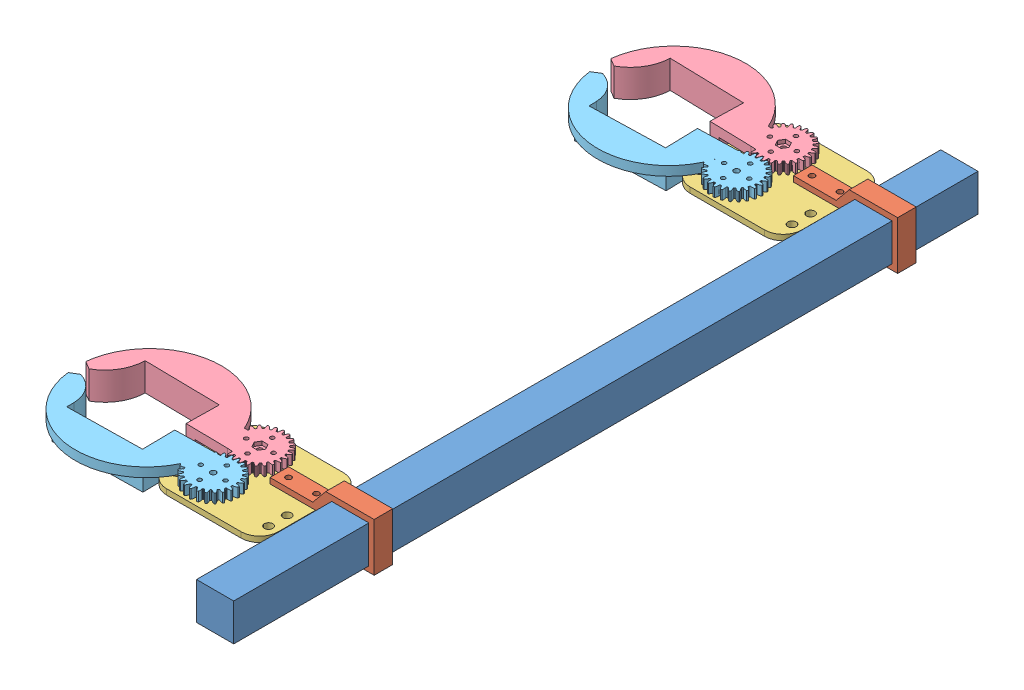
SolidWorks assembly 连接件部分ver1, configuration Default. Lengths in mm.
Overall size (157.66 26.1 400).
9 component instances, 5 part files, 23 mates.
Components (placement in the parent):
- 横杆的简易模型-1: 横杆的简易模型 [默认] at origin size (20 20 400)
- 连接件-1: 连接件 [默认] at (-24.8405 13.4666 36.1997) size (56 26 10)
- 固定舵机盘-1: 固定舵机盘 [默认] at (-24.824 10.0166 49.6672) x (-1 0 0) z (0 1 0) size (60 55 7)
- 右臂直齿M1X25-1: 右臂直齿M1X25 [M1X25] at (-70.3405 20.0166 36.0997) x (-0.026433 0 0.999651) z (0 -1 0) size (39.61 99.26 15)
- 左臂直齿M1X25-1: 左臂直齿M1X25 [M1X25] at (-70.3405 15.0166 61.1997) x (-0.026433 0 -0.999651) z (0 1 0) size (39.22 98.93 15)
- 左臂直齿M1X25-2: 左臂直齿M1X25 [M1X25] at (-70.4405 15.1166 342.4288) x (-0.015806 0 -0.999875) z (0 1 0) size (39.22 98.93 15)
- 右臂直齿M1X25-2: 右臂直齿M1X25 [M1X25] at (-70.4405 20.1166 317.3288) x (-0.015806 0 0.999875) z (0 -1 0) size (39.61 99.26 15)
- 固定舵机盘-2: 固定舵机盘 [默认] at (-24.924 10.1166 330.8963) x (-1 0 0) z (0 1 0) size (60 55 7)
- 连接件-2: 连接件 [默认] at (-24.9405 13.5666 317.4288) size (56 26 10)
Mates (geometry in assembly coordinates):
- 平行2: parallel anti-aligned: plane of 横杆的简易模型-1 through (-1.8405 23.4666 400) normal (1 0 0); plane of 连接件-1 through (-1.7405 23.4666 16.1997) normal (-1 0 0)
- 平行5: parallel anti-aligned: plane of 横杆的简易模型-1 through (-21.8405 23.4666 400) normal (-1 0 0); plane of 连接件-1 through (-21.8405 23.4666 16.1997) normal (1 0 0)
- 重合6: coincident anti-aligned: plane of 横杆的简易模型-1 through (-21.8405 23.4666 400) normal (0 1 0); plane of 连接件-1 through (-1.7405 23.4666 16.1997) normal (0 -1 0)
- 重合8: coincident anti-aligned: line of 横杆的简易模型-1 through (-21.8405 23.4666 400) axis (0 0 -1); line of 连接件-1 through (-21.8405 23.4666 36.1997) axis (0 0 1)
- 同心1: concentric anti-aligned: circle of 连接件-1; cylinder of 固定舵机盘-1 through (-34.8405 5.0166 41.1997) axis (0 1 0) radius 1.5
- 重合9: coincident anti-aligned: circle of 连接件-1; cylinder of 固定舵机盘-1 through (-49.8405 5.0166 41.1997) axis (0 1 0) radius 1.5
- 重合10: coincident anti-aligned: plane of 连接件-1 through (-54.8405 15.0166 46.1997) normal (0 -1 0); plane of 固定舵机盘-1 through (-24.824 15.0166 49.6672) normal (0 1 0)
- 同心2: concentric aligned: cylinder of 固定舵机盘-1 through (-70.3405 15.0166 36.0997) axis (0 -1 0) radius 1.5; cylinder of 右臂直齿M1X25-1 through (-70.3405 20.0166 36.0997) axis (0 -1 0) radius 1.5
- 同心3: concentric anti-aligned: circle of 固定舵机盘-1; cylinder of 左臂直齿M1X25-1 through (-70.3405 5.0166 61.1997) axis (0 1 0) radius 1.5
- 齿轮配合1: gear = 25 : 25 mm: cylinder of 右臂直齿M1X25-1 through (-70.3405 15.0166 36.0997) axis (0 1 0) radius 13.5; cylinder of 左臂直齿M1X25-1 through (-70.3405 20.0166 61.1997) axis (0 -1 0) radius 13.5
- 同心4: concentric anti-aligned: cylinder of 固定舵机盘-2 through (-34.9405 5.1166 322.4288) axis (0 1 0) radius 1.5; circle of 连接件-2
- 重合14: coincident anti-aligned: cylinder of 固定舵机盘-2 through (-49.9405 5.1166 322.4288) axis (0 1 0) radius 1.5; circle of 连接件-2
- 重合15: coincident anti-aligned: plane of 固定舵机盘-2 through (-24.924 15.1166 330.8963) normal (0 1 0); plane of 连接件-2 through (-54.9405 15.1166 327.4288) normal (0 -1 0)
- 重合16: coincident aligned: plane of 左臂直齿M1X25-2 through (-70.4405 20.1166 342.4288) normal (0 1 0); plane of 右臂直齿M1X25-2 through (-70.4405 20.1166 317.3288) normal (0 1 0)
- 同心5: concentric aligned: cylinder of 右臂直齿M1X25-2 through (-70.4405 20.1166 317.3288) axis (0 -1 0) radius 1.5; cylinder of 固定舵机盘-2 through (-70.4405 15.1166 317.3288) axis (0 -1 0) radius 1.5
- 同心6: concentric anti-aligned: cylinder of 左臂直齿M1X25-2 through (-70.4405 5.1166 342.4288) axis (0 1 0) radius 1.5; circle of 固定舵机盘-2
- 平行6: parallel anti-aligned: plane of 横杆的简易模型-1 through (-21.8405 23.4666 400) normal (0 1 0); plane of 连接件-2 through (-1.8405 23.5666 297.4288) normal (0 -1 0)
- 重合20: coincident anti-aligned: plane of 横杆的简易模型-1 through (-1.8405 23.4666 400) normal (1 0 0); plane of 连接件-2 through (-1.8405 23.5666 297.4288) normal (-1 0 0)
- 重合21: coincident anti-aligned: plane of 横杆的简易模型-1 through (-1.8405 3.4666 400) normal (0 -1 0); plane of 连接件-2 through (-21.9405 3.4666 297.4288) normal (0 1 0)
- 齿轮配合4: gear = 25 : 25 mm: cylinder of 右臂直齿M1X25-2 through (-70.4405 15.1166 317.3288) axis (0 1 0) radius 13.5; cylinder of 左臂直齿M1X25-2 through (-70.4405 20.1166 342.4288) axis (0 -1 0) radius 13.5
- 重合22: coincident aligned: plane of 右臂直齿M1X25-1 through (-70.3405 20.0166 36.0997) normal (0 1 0); plane of 左臂直齿M1X25-1 through (-70.3405 20.0166 61.1997) normal (0 1 0)
- 重合26: coincident anti-aligned: plane of 左臂直齿M1X25-2 through (-70.4405 15.1166 342.4288) normal (0 -1 0); plane of 固定舵机盘-2 through (-24.924 15.1166 330.8963) normal (0 1 0)
- 重合27: coincident anti-aligned: plane of 固定舵机盘-1 through (-24.824 15.0166 49.6672) normal (0 1 0); plane of 左臂直齿M1X25-1 through (-70.3405 15.0166 61.1997) normal (0 -1 0)
